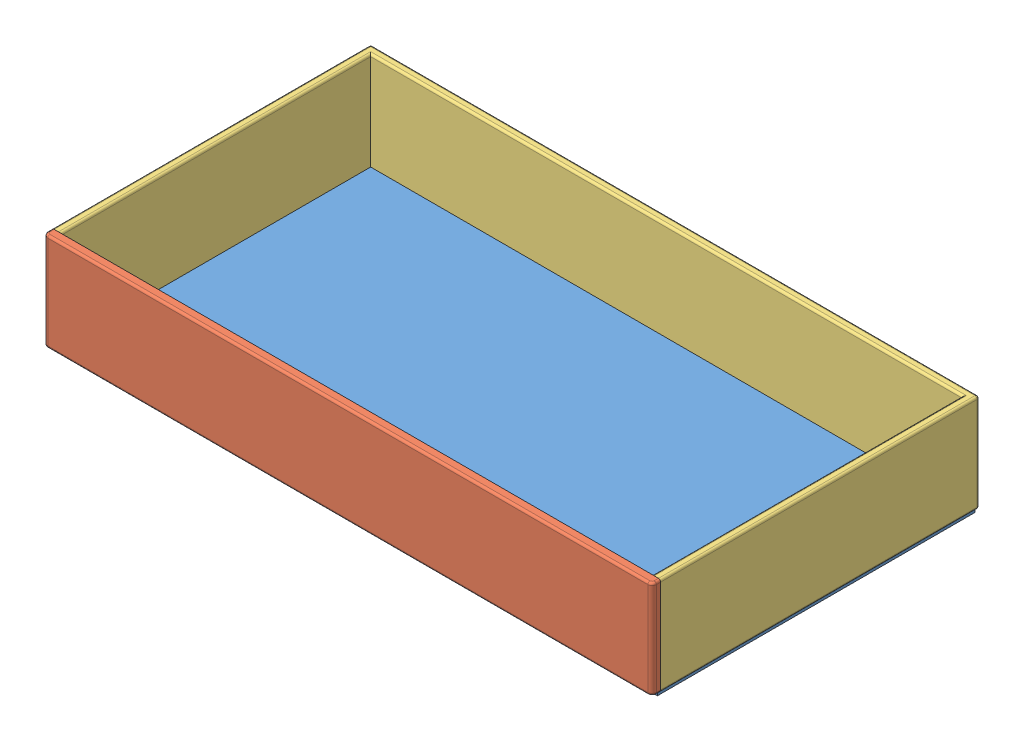
SolidWorks assembly Box, configuration Standard. Lengths in mm.
Overall size (1422.41 290.86 765.47).
15 component instances, 5 part files, 21 mates.
Components (placement in the parent):
- Box-Boden-1: Box-Boden [Standard] at (1050 396.1981 646.6526) x (1 0 0) z (0 1 0) size (1410 741.08 8)
- Box-Front-1: Box-Front [Standard] at (1050 396.1981 646.6526) x (1 0 0) z (0 1 0) size (1420.62 20.02 228.82)
- Box-Rahmen-1: Box-Rahmen [Standard] at (1050 396.1981 646.6526) x (1 0 0) z (0 1 0) size (1422.41 745.45 228.79)
- Rolle-1: Rolle [Standard] at (83.2536 0 -67.2675) size (28.61 54.54 53.59)
  - Rolle-1: Rolle [Standard] at (1010.388 1040.9998 -976.2734) x (1 0 0) z (0 -0.414368 -0.91011) size (23.76 40.47 40.46)
  - Rollenhalter-1: Rollenhalter [Standard] at (1010.388 396.1981 1340.927) x (1 0 0) z (0 1 0) size (28.61 51.43 30.62)
- Rolle-2: Rolle [Standard] at (1365 0 -67.2675) size (28.61 54.54 53.59)
  - Rolle-1: Rolle [Standard] at (1010.388 1040.9998 -976.2734) x (1 0 0) z (0 -0.414368 -0.91011) size (23.76 40.47 40.46)
  - Rollenhalter-1: Rollenhalter [Standard] at (1010.388 396.1981 1340.927) x (1 0 0) z (0 1 0) size (28.61 51.43 30.62)
- Rolle-3: Rolle [Standard] at (1365 0 -657.2782) size (28.61 54.54 53.59)
  - Rolle-1: Rolle [Standard] at (1010.388 1040.9998 -976.2734) x (1 0 0) z (0 -0.414368 -0.91011) size (23.76 40.47 40.46)
  - Rollenhalter-1: Rollenhalter [Standard] at (1010.388 396.1981 1340.927) x (1 0 0) z (0 1 0) size (28.61 51.43 30.62)
- Rolle-4: Rolle [Standard] at (83.2536 0 -657.2782) size (28.61 54.54 53.59)
  - Rolle-1: Rolle [Standard] at (1010.388 1040.9998 -976.2734) x (1 0 0) z (0 -0.414368 -0.91011) size (23.76 40.47 40.46)
  - Rollenhalter-1: Rollenhalter [Standard] at (1010.388 396.1981 1340.927) x (1 0 0) z (0 1 0) size (28.61 51.43 30.62)
Mates (geometry in assembly coordinates):
- Deckungsgleich1: coincident anti-aligned: plane of Box-Boden-1 through (743.0666 8 -17.2675) normal (0 1 0); plane of Box-Rahmen-1 through (188.943 179.895 -97.3165) normal (0 -1 0)
- Deckungsgleich2: coincident: plane of Box-Front-1 through (1420 8 -20) normal (0 0 -1); plane of Box-Rahmen-1 through (-86.2939 -99.9756 -20) normal (0 0 1)
- Deckungsgleich3: coincident anti-aligned: plane of Box-Boden-1 through (-666.9334 8 -758.3474) normal (0 0 -1); line of Box-Rahmen-1 through (-1226.057 179.895 -855.6639) axis (1 0 0)
- Deckungsgleich4: coincident aligned: plane of Box-Front-1 through (-671.9334 236.1981 -20) normal (0 1 0); plane of Box-Rahmen-1 through (188.943 408.0932 -97.3165) normal (0 1 0)
- Deckungsgleich5: coincident aligned: plane of Box-Front-1 through (748.0666 236.1981 -763.3474) normal (1 0 0); plane of Box-Rahmen-1 through (188.943 408.0932 -860.6639) normal (1 0 0)
- Deckungsgleich6: coincident: plane of Box-Boden-1 through (-666.9334 8 -17.2675) normal (-1 0 0); line of Box-Rahmen-1 through (-1226.057 179.895 -117.3165) axis (0 0 -1)
- Deckungsgleich7: coincident anti-aligned: plane of ? through (1415 0 -17.2675) normal (0 -1 0)
- Deckungsgleich8: coincident aligned: plane of ? through (1420 236.1981 0) normal (0 0 1)
- Deckungsgleich9: coincident anti-aligned: plane of ? through (0 236.1981 0) normal (-1 0 0)
- Deckungsgleich10: coincident: plane of Box-Boden-1 through (1415 0 -17.2675) normal (0 -1 0); plane of Rolle-1/Rollenhalter-1 through (57.5 0 -65.4636) normal (0 1 0)
- Deckungsgleich11: coincident: plane of Box-Boden-1 through (1415 0 -17.2675) normal (0 -1 0); plane of Rolle-2/Rollenhalter-1 through (1339.2464 0 -65.4636) normal (0 1 0)
- Deckungsgleich12: coincident: plane of Box-Boden-1 through (1415 0 -17.2675) normal (0 -1 0); plane of Rolle-3/Rollenhalter-1 through (1339.2464 0 -655.4744) normal (0 1 0)
- Deckungsgleich13: coincident: plane of Box-Boden-1 through (1415 0 -17.2675) normal (0 -1 0); plane of Rolle-4/Rollenhalter-1 through (57.5 0 -655.4744) normal (0 1 0)
- Abstand1: distance = 50 mm: line of Rolle-4/Rollenhalter-1 through (80.7536 0 -708.3474) axis (-1 0 0); plane of Box-Boden-1 through (5 8 -758.3474) normal (0 0 -1)
- Abstand2: distance = 50 mm aligned: plane of Rolle-4/Rollenhalter-1 through (55 -30.1719 -657.8582) normal (-1 0 0); plane of Box-Boden-1 through (5 8 -17.2675) normal (-1 0 0)
- Abstand3: distance = 50 mm: plane of Rolle-1/Rollenhalter-1 through (55 -30.1719 -67.8474) normal (-1 0 0); plane of Box-Boden-1 through (5 8 -17.2675) normal (-1 0 0)
- Abstand4: distance = 50 mm: line of Rolle-1/Rollenhalter-1 through (57.5 0 -67.2675) axis (1 0 0); plane of Box-Boden-1 through (1415 8 -17.2675) normal (0 0 1)
- Abstand5: distance = 50 mm: line of Rolle-2/Rollenhalter-1 through (1339.2464 0 -67.2675) axis (1 0 0); plane of Box-Boden-1 through (1415 8 -17.2675) normal (0 0 1)
- Abstand6: distance = 50 mm aligned: plane of Rolle-2/Rollenhalter-1 through (1365 -30.1719 -67.8474) normal (1 0 0); plane of Box-Boden-1 through (1415 8 -758.3474) normal (1 0 0)
- Abstand7: distance = 50 mm: plane of Rolle-3/Rollenhalter-1 through (1365 -30.1719 -657.8582) normal (1 0 0); plane of Box-Boden-1 through (1415 8 -758.3474) normal (1 0 0)
- Abstand8: distance = 50 mm: line of Rolle-3/Rollenhalter-1 through (1362.5 0 -708.3474) axis (-1 0 0); plane of Box-Boden-1 through (5 8 -758.3474) normal (0 0 -1)
